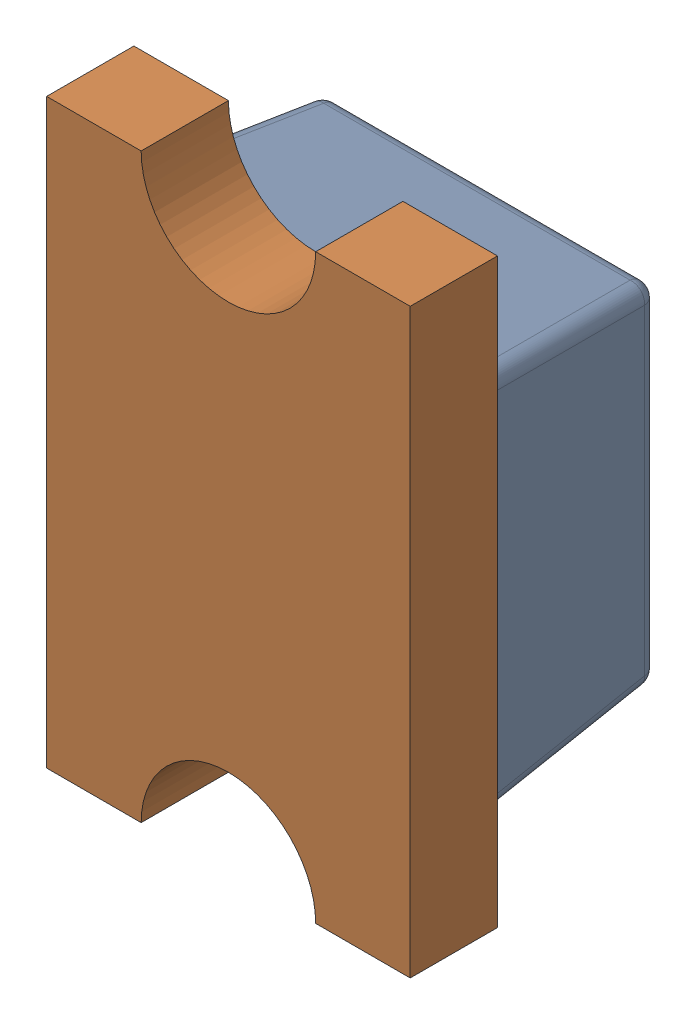
SolidWorks assembly D2_XLR2, configuration Default. Lengths in mm.
Overall size (1.25 2 0.9).
2 component instances, 2 part files, 0 mates.
Components (placement in the parent):
- LED 0805 Lens RED-1: LED 0805 Lens RED [Default] at (133.043 70.1359 -1.2114) x (0 -1 0) z (1 0 0) size (1.3 0.6 1.25)
- LED 0805 Base RED-1: LED 0805 Base RED [Default] at (133.043 70.1359 -1.2114) x (0 -1 0) z (1 0 0) size (2 0.4 1.25)
